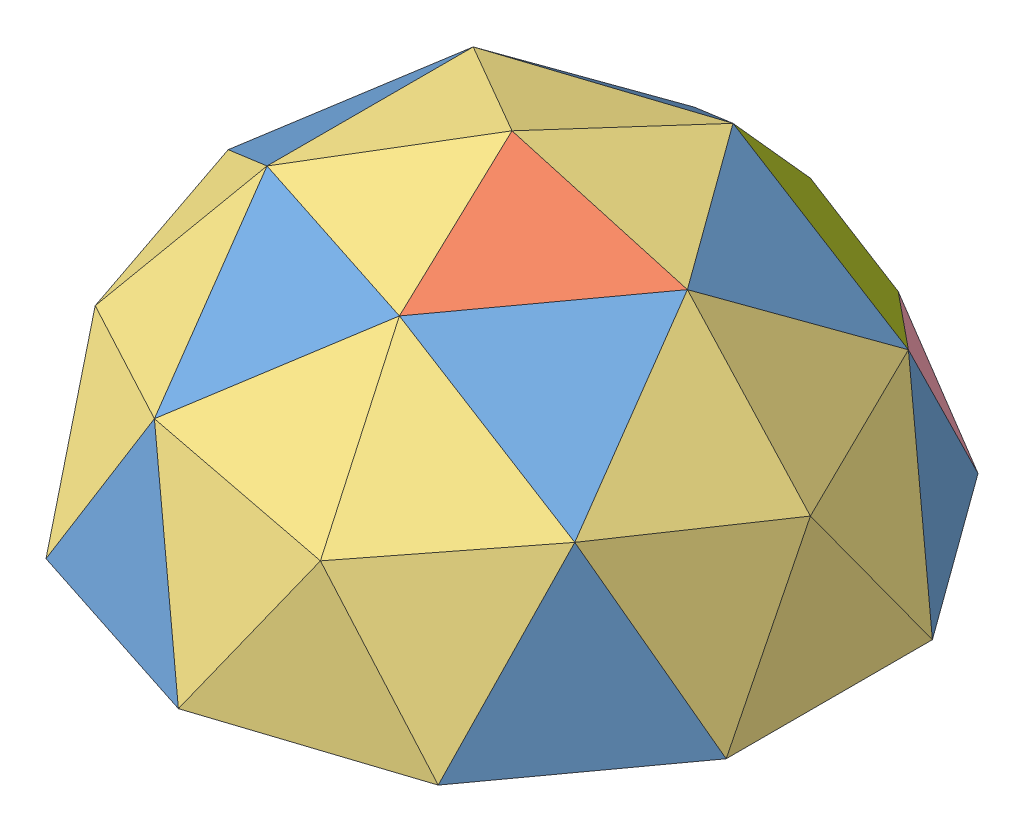
SolidWorks assembly Geocorkwithdoor1.0, configuration По умолчанию. Lengths in mm.
Overall size (6144.42 3896.71 6678.72).
46 component instances, 8 part files, 28 mates.
Components (placement in the parent):
- BBB^Geocorkwithdoor1.0-38: BBB^Geocorkwithdoor1.0 [По умолчанию] at (-850.6508 525.7311 2618.034) x (-0.952822 -0.059759 -0.29759) z (0.303531 -0.187592 -0.934172) size (1850.67 1659.13 60) (virtual)
- Copy of AAB^Geocorkwithdoor1.0-78: Copy of AAB^Geocorkwithdoor1.0 [По умолчанию] at (758.6906 2670.7024 551.221) x (-0.963409 0.262502 0.054179) z (-0.268035 -0.943522 -0.194739) size (1637.1 1559.6 60) (virtual)
- Copy of AAB^Geocorkwithdoor1.0-79: AAB^Geocorkwithdoor1.0 [По умолчанию] at (-289.794 2670.7024 891.8943) x (-0.349237 0.262502 -0.899514) z (0.10238 -0.943522 -0.315094) size (1637.1 1559.6 60) (virtual)
- Copy of AAB^Geocorkwithdoor1.0-80: AAB^Geocorkwithdoor1.0 [По умолчанию] at (-937.7931 2670.7024 0) x (0.747569 0.262502 -0.61011) z (0.331309 -0.943522 0) size (1637.1 1559.6 60) (virtual)
- Copy of AAB^Geocorkwithdoor1.0-81: AAB^Geocorkwithdoor1.0 [По умолчанию] at (-289.794 2670.7024 -891.8943) x (0.81126 0.262502 0.522446) z (0.10238 -0.943522 0.315094) size (1637.1 1559.6 60) (virtual)
- Copy of AAB^Geocorkwithdoor1.0-82: AAB^Geocorkwithdoor1.0 [По умолчанию] at (758.6906 2670.7024 -551.221) x (-0.246182 0.262502 0.932999) z (-0.268035 -0.943522 0.194739) size (1637.1 1559.6 60) (virtual)
- BBB^Geocorkwithdoor1.0-39: BBB^Geocorkwithdoor1.0 [По умолчанию] at (-2752.7638 525.7311 0) x (-0.011413 -0.059759 -0.998148) z (0.982247 -0.187592 0) size (1850.67 1659.13 60) (virtual)
- BBB^Geocorkwithdoor1.0-40: BBB^Geocorkwithdoor1.0 [По умолчанию] at (-850.6508 525.7311 -2618.034) x (0.945768 -0.059759 -0.319299) z (0.303531 -0.187592 0.934172) size (1850.67 1659.13 60) (virtual)
- BBB^Geocorkwithdoor1.0-41: BBB^Geocorkwithdoor1.0 [По умолчанию] at (2227.0327 525.7311 -1618.034) x (0.59593 -0.059759 0.80081) z (-0.794654 -0.187592 0.57735) size (1850.67 1659.13 60) (virtual)
- BBB^Geocorkwithdoor1.0-42: BBB^Geocorkwithdoor1.0 [По умолчанию] at (2227.0327 525.7311 1618.034) x (-0.577463 -0.059759 0.814227) z (-0.794654 -0.187592 -0.57735) size (1850.67 1659.13 60) (virtual)
- BBB^Geocorkwithdoor1.0-43: BBB^Geocorkwithdoor1.0 [По умолчанию] at (-525.7311 2227.0327 1618.034) x (0.964235 0.036933 0.262464) z (0.187592 -0.794654 -0.57735) size (1850.67 1659.13 60) (virtual)
- Copy of AAB^Geocorkwithdoor1.0-83: AAB^Geocorkwithdoor1.0 [По умолчанию] at (-70.0293 935.1748 2670.7024) x (0.457316 0.843008 -0.283197) z (0.02474 -0.330384 -0.943522) size (1637.1 1559.6 60) (virtual)
- Copy of AAB^Geocorkwithdoor1.0-88: AAB^Geocorkwithdoor1.0 [По умолчанию] at (1626.4544 935.1748 2119.4814) x (-0.734672 -0.194973 0.649802) z (-0.574604 -0.330384 -0.748783) size (1637.1 1559.6 60) (virtual)
- Copy of AAB^Geocorkwithdoor1.0-93: AAB^Geocorkwithdoor1.0 [По умолчанию] at (867.7638 355.5867 2670.7024) x (-0.611006 0.78604 0.093872) z (-0.306569 -0.125624 -0.943522) size (1637.1 1559.6 60) (virtual)
- Copy of AAB^Geocorkwithdoor1.0-98: AAB^Geocorkwithdoor1.0 [По умолчанию] at (109.0732 1872.9679 2119.4814) x (0.99391 -0.102798 0.039693) z (-0.038534 -0.661694 -0.748783) size (1637.1 1559.6 60) (virtual)
- Copy of AAB^Geocorkwithdoor1.0-103: AAB^Geocorkwithdoor1.0 [По умолчанию] at (1157.5578 1872.9679 1778.8081) x (0.257221 -0.744305 0.616318) z (-0.408949 -0.661694 -0.628428) size (1637.1 1559.6 60) (virtual)
- Copy of AAB^Geocorkwithdoor1.0-84: AAB^Geocorkwithdoor1.0 [По умолчанию] at (-2561.6291 935.1748 758.6906) x (0.410654 0.843008 0.347421) z (0.904988 -0.330384 -0.268035) size (1637.1 1559.6 60) (virtual)
- Copy of AAB^Geocorkwithdoor1.0-85: AAB^Geocorkwithdoor1.0 [По умолчанию] at (-1513.1446 935.1748 -2201.8058) x (-0.203517 0.843008 0.497914) z (0.534573 -0.330384 0.777868) size (1637.1 1559.6 60) (virtual)
- Copy of AAB^Geocorkwithdoor1.0-86: AAB^Geocorkwithdoor1.0 [По умолчанию] at (1626.4544 935.1748 -2119.4814) x (-0.536435 0.843008 -0.039693) z (-0.574604 -0.330384 0.748783) size (1637.1 1559.6 60) (hidden, virtual)
- Copy of AAB^Geocorkwithdoor1.0-87: AAB^Geocorkwithdoor1.0 [По умолчанию] at (2518.3486 935.1748 891.8943) x (-0.128018 0.843008 -0.522446) z (-0.889698 -0.330384 -0.315094) size (1637.1 1559.6 60) (virtual)
- Copy of AAB^Geocorkwithdoor1.0-94: AAB^Geocorkwithdoor1.0 [По умолчанию] at (-2271.8351 355.5867 1650.5848) x (-0.278089 0.78604 -0.552094) z (0.802608 -0.125624 -0.583129) size (1637.1 1559.6 60) (virtual)
- Copy of AAB^Geocorkwithdoor1.0-95: AAB^Geocorkwithdoor1.0 [По умолчанию] at (-2271.8351 355.5867 -1650.5848) x (0.439138 0.78604 -0.435084) z (0.802608 -0.125624 0.583129) size (1637.1 1559.6 60) (virtual)
- Copy of AAB^Geocorkwithdoor1.0-96: AAB^Geocorkwithdoor1.0 [По умолчанию] at (867.7638 355.5867 -2670.7024) x (0.549491 0.78604 0.283197) z (-0.306569 -0.125624 0.943522) size (1637.1 1559.6 60) (hidden, virtual)
- Copy of AAB^Geocorkwithdoor1.0-97: AAB^Geocorkwithdoor1.0 [По умолчанию] at (2808.1427 355.5867 0) x (-0.099534 0.78604 0.61011) z (-0.992078 -0.125624 0) size (1637.1 1559.6 60) (virtual)
- Copy of AAB^Geocorkwithdoor1.0-89: AAB^Geocorkwithdoor1.0 [По умолчанию] at (-1513.1446 935.1748 2201.8058) x (-0.845025 -0.194973 -0.497914) z (0.534573 -0.330384 -0.777868) size (1637.1 1559.6 60) (virtual)
- Copy of AAB^Geocorkwithdoor1.0-90: AAB^Geocorkwithdoor1.0 [По умолчанию] at (-2561.6291 935.1748 -758.6906) x (0.212418 -0.194973 -0.95753) z (0.904988 -0.330384 0.268035) size (1637.1 1559.6 60) (virtual)
- Copy of AAB^Geocorkwithdoor1.0-91: AAB^Geocorkwithdoor1.0 [По умолчанию] at (-70.0293 935.1748 -2670.7024) x (0.976306 -0.194973 -0.093872) z (0.02474 -0.330384 0.943522) size (1637.1 1559.6 60) (hidden, virtual)
- Copy of AAB^Geocorkwithdoor1.0-92: AAB^Geocorkwithdoor1.0 [По умолчанию] at (2518.3486 935.1748 -891.8943) x (0.390973 -0.194973 0.899514) z (-0.889698 -0.330384 0.315094) size (1637.1 1559.6 60) (virtual)
- Copy of AAB^Geocorkwithdoor1.0-104: AAB^Geocorkwithdoor1.0 [По умолчанию] at (-1334.042 1872.9679 1650.5848) x (-0.506667 -0.744305 0.435084) z (0.471299 -0.661694 -0.583129) size (1637.1 1559.6 60) (virtual)
- Copy of AAB^Geocorkwithdoor1.0-105: AAB^Geocorkwithdoor1.0 [По умолчанию] at (-1982.0411 1872.9679 -758.6906) x (-0.570359 -0.744305 -0.347421) z (0.700228 -0.661694 0.268035) size (1637.1 1559.6 60) (virtual)
- Copy of AAB^Geocorkwithdoor1.0-106: AAB^Geocorkwithdoor1.0 [По умолчанию] at (109.0732 1872.9679 -2119.4814) x (0.154166 -0.744305 -0.649802) z (-0.038534 -0.661694 0.748783) size (1637.1 1559.6 60) (hidden, virtual)
- Copy of AAB^Geocorkwithdoor1.0-107: AAB^Geocorkwithdoor1.0 [По умолчанию] at (2049.4521 1872.9679 -551.221) x (0.665639 -0.744305 -0.054179) z (-0.724043 -0.661694 0.194739) size (1637.1 1559.6 60) (virtual)
- Copy of AAB^Geocorkwithdoor1.0-99: AAB^Geocorkwithdoor1.0 [По умолчанию] at (-1982.0411 1872.9679 758.6906) x (0.269385 -0.102798 0.95753) z (0.700228 -0.661694 -0.268035) size (1637.1 1559.6 60) (virtual)
- Copy of AAB^Geocorkwithdoor1.0-100: AAB^Geocorkwithdoor1.0 [По умолчанию] at (-1334.042 1872.9679 -1650.5848) x (-0.827421 -0.102798 0.552094) z (0.471299 -0.661694 0.583129) size (1637.1 1559.6 60) (virtual)
- Copy of AAB^Geocorkwithdoor1.0-101: AAB^Geocorkwithdoor1.0 [По умолчанию] at (1157.5578 1872.9679 -1778.8081) x (-0.780759 -0.102798 -0.616318) z (-0.408949 -0.661694 0.628428) size (1637.1 1559.6 60) (hidden, virtual)
- Copy of AAB^Geocorkwithdoor1.0-102: AAB^Geocorkwithdoor1.0 [По умолчанию] at (2049.4521 1872.9679 551.221) x (0.344885 -0.102798 -0.932999) z (-0.724043 -0.661694 -0.194739) size (1637.1 1559.6 60) (virtual)
- BBB^Geocorkwithdoor1.0-44: BBB^Geocorkwithdoor1.0 [По умолчанию] at (-1701.3016 2227.0327 0) x (0.048346 0.036933 0.998148) z (0.607062 -0.794654 0) size (1850.67 1659.13 60) (virtual)
- BBB^Geocorkwithdoor1.0-45: BBB^Geocorkwithdoor1.0 [По умолчанию] at (-525.7311 2227.0327 -1618.034) x (-0.934355 0.036933 0.354425) z (0.187592 -0.794654 0.57735) size (1850.67 1659.13 60) (virtual)
- BBB^Geocorkwithdoor1.0-46: BBB^Geocorkwithdoor1.0 [По умолчанию] at (1376.3819 2227.0327 -1000) x (-0.62581 0.036933 -0.779101) z (-0.491123 -0.794654 0.356822) size (1850.67 1659.13 60) (virtual)
- BBB^Geocorkwithdoor1.0-47: BBB^Geocorkwithdoor1.0 [По умолчанию] at (1376.3819 2227.0327 1000) x (0.547583 0.036933 -0.835936) z (-0.491123 -0.794654 -0.356822) size (1850.67 1659.13 60) (virtual)
- Copy of Geocorkdoor1.0^Geocorkwithdoor1.0-1: Copy of Geocorkdoor1.0^Geocorkwithdoor1.0 [Default] at (881.6889 -0.008 -2713.4939) x (0.951065 0.000009 0.30899) z (-0.276364 -0.447222 0.850656) size (4035.57 3131.62 726.08) (virtual)
  - Copy of AABdoorright1.0^Copy of Geocorkdoor1.0_Geocorkwithdoor1.0-1: Copy of AABdoorright1.0^Copy of Geocorkdoor1.0_Geocorkwithdoor1.0 [По умолчанию] at (891.8707 986.1815 -118.7551) x (-0.522446 0.811256 -0.262514) z (-0.315108 0.102383 0.943517) size (1384.15 1469.04 60) (virtual)
  - Copy of AABdoortopright1.0^Copy of Geocorkdoor1.0_Geocorkwithdoor1.0-2: Copy of AABdoortopright1.0^Copy of Geocorkdoor1.0_Geocorkwithdoor1.0 [По умолчанию] at (-0.0202 338.1813 -118.7551) x (0.61011 0.747565 -0.262514) z (0 0.331324 0.943517) size (1637.1 1559.6 60) (hidden, virtual)
  - Copy of AABdoortopleft1.0^Copy of Geocorkdoor1.0_Geocorkwithdoor1.0-3: Copy of AABdoortopleft1.0^Copy of Geocorkdoor1.0_Geocorkwithdoor1.0 [По умолчанию] at (-891.9112 986.1815 -118.7551) x (0.899509 -0.349243 -0.262514) z (0.315108 0.102383 0.943517) size (1131.21 1514.32 60) (virtual)
  - Copy of AABdoorleft1.0^Copy of Geocorkdoor1.0_Geocorkwithdoor1.0-5: Copy of AABdoorleft1.0^Copy of Geocorkdoor1.0_Geocorkwithdoor1.0 [По умолчанию] at (-551.2304 2034.6615 -118.7551) x (-0.054191 -0.963405 -0.262514) z (0.194745 -0.268049 0.943517) size (1384.15 1514.32 60) (virtual)
  - Copy of AABdoorbase1.0^Copy of Geocorkdoor1.0_Geocorkwithdoor1.0-8: Copy of AABdoorbase1.0^Copy of Geocorkdoor1.0_Geocorkwithdoor1.0 [По умолчанию] at (551.2094 2034.6473 -118.7551) x (-0.933 -0.246165 -0.262514) z (-0.194751 -0.268044 0.943517) size (1384.15 1514.32 60) (virtual)
Mates (geometry in assembly coordinates):
- На месте1: in place: plane of ? through (-70.8876 43.8109 218.1695) normal (0.303531 -0.187592 -0.934172); moOrthogonalPlaneRef_w of ?; unknown of ?; unknown of BBB^Geocorkwithdoor1.0-38
- Совпадение1: coincident: plane of assembly; plane of BBB^Geocorkwithdoor1.0-38; plane of assembly
- Совпадение2: coincident: plane of assembly; plane of BBB^Geocorkwithdoor1.0-38 through (-850.6508 525.7311 2618.034) normal (0 0.980427 -0.196881); moOrthogonalPlaneRef_w of assembly
- Совпадение3: coincident: plane of assembly; plane of BBB^Geocorkwithdoor1.0-38 through (-850.6508 525.7311 2618.034) normal (-0.952822 -0.059759 -0.29759); moOrthogonalPlaneRef_w of assembly
- На месте2: in place: plane of ? through (63.2242 222.5585 45.9351) normal (-0.268035 -0.943522 -0.194739); unknown of ?; unknown of ?; unknown of Copy of AAB^Geocorkwithdoor1.0-78
- Совпадение4: coincident: plane of assembly; plane of Copy of AAB^Geocorkwithdoor1.0-78; plane of assembly
- Совпадение5: coincident: plane of assembly; plane of Copy of AAB^Geocorkwithdoor1.0-78 through (758.6906 2670.7024 551.221) normal (0 0.202135 -0.979358); moOrthogonalPlaneRef_w of assembly
- Совпадение6: coincident: plane of assembly; plane of Copy of AAB^Geocorkwithdoor1.0-78 through (758.6906 2670.7024 551.221) normal (-0.963409 0.262502 0.054179); moOrthogonalPlaneRef_w of assembly
- Совпадение8: coincident: point of assembly; point of assembly; point of Copy of AAB^Geocorkwithdoor1.0-79; point of BBB^Geocorkwithdoor1.0-43
- Совпадение11: coincident: point of assembly; point of assembly; point of Copy of AAB^Geocorkwithdoor1.0-79; point of BBB^Geocorkwithdoor1.0-43
- Совпадение12: coincident: point of assembly; point of assembly; point of BBB^Geocorkwithdoor1.0-38; point of BBB^Geocorkwithdoor1.0-43
- Совпадение13: coincident: point of assembly; point of assembly; point of BBB^Geocorkwithdoor1.0-38; point of Copy of AAB^Geocorkwithdoor1.0-83
- Совпадение15: coincident: point of assembly; point of Copy of AAB^Geocorkwithdoor1.0-83; point of assembly
- Совпадение16: coincident: point of assembly; point of Copy of AAB^Geocorkwithdoor1.0-88; point of assembly
- Совпадение17: coincident: point of assembly; point of assembly; point of BBB^Geocorkwithdoor1.0-42; point of Copy of AAB^Geocorkwithdoor1.0-88
- Совпадение18: coincident: point of assembly; point of assembly; point of Copy of AAB^Geocorkwithdoor1.0-83; point of Copy of AAB^Geocorkwithdoor1.0-88
- Совпадение23: coincident: point of assembly; point of Copy of AAB^Geocorkwithdoor1.0-93; point of assembly
- Совпадение24: coincident: point of assembly; point of Copy of AAB^Geocorkwithdoor1.0-93; point of assembly
- Совпадение25: coincident: point of assembly; point of assembly; point of Copy of AAB^Geocorkwithdoor1.0-88; point of Copy of AAB^Geocorkwithdoor1.0-93
- Совпадение26: coincident: point of assembly; point of assembly; point of Copy of AAB^Geocorkwithdoor1.0-78; point of Copy of AAB^Geocorkwithdoor1.0-98
- Совпадение27: coincident: point of assembly; point of assembly; point of BBB^Geocorkwithdoor1.0-38; point of Copy of AAB^Geocorkwithdoor1.0-98
- Совпадение28: coincident: point of assembly; point of assembly; point of Copy of AAB^Geocorkwithdoor1.0-88; point of Copy of AAB^Geocorkwithdoor1.0-98
- Совпадение29: coincident: point of assembly; point of assembly; point of Copy of AAB^Geocorkwithdoor1.0-98; point of Copy of AAB^Geocorkwithdoor1.0-103
- Совпадение30: coincident: point of assembly; point of assembly; point of Copy of AAB^Geocorkwithdoor1.0-88; point of Copy of AAB^Geocorkwithdoor1.0-103
- Совпадение31: coincident: point of assembly; point of assembly; point of Copy of AAB^Geocorkwithdoor1.0-98; point of Copy of AAB^Geocorkwithdoor1.0-103
- Coincident1: coincident: plane of assembly; plane of assembly; plane of BBB^Geocorkwithdoor1.0-41 through (1871.853 772.666 -1922.7399) normal (-0.702211 0.455662 -0.547057); plane of Copy of Geocorkdoor1.0^Geocorkwithdoor1.0-1/Copy of AABdoorright1.0^Copy of Geocorkdoor1.0_Geocorkwithdoor1.0-1 through (1871.853 772.666 -1922.7399) normal (0.702211 -0.455662 0.547057)
- Coincident4: coincident: point of assembly; point of assembly; point of Copy of AAB^Geocorkwithdoor1.0-92; point of Copy of Geocorkdoor1.0^Geocorkwithdoor1.0-1/Copy of AABdoorright1.0^Copy of Geocorkdoor1.0_Geocorkwithdoor1.0-1
- Coincident5: coincident: point of assembly; point of assembly; point of BBB^Geocorkwithdoor1.0-41; point of Copy of Geocorkdoor1.0^Geocorkwithdoor1.0-1/Copy of AABdoorright1.0^Copy of Geocorkdoor1.0_Geocorkwithdoor1.0-1
